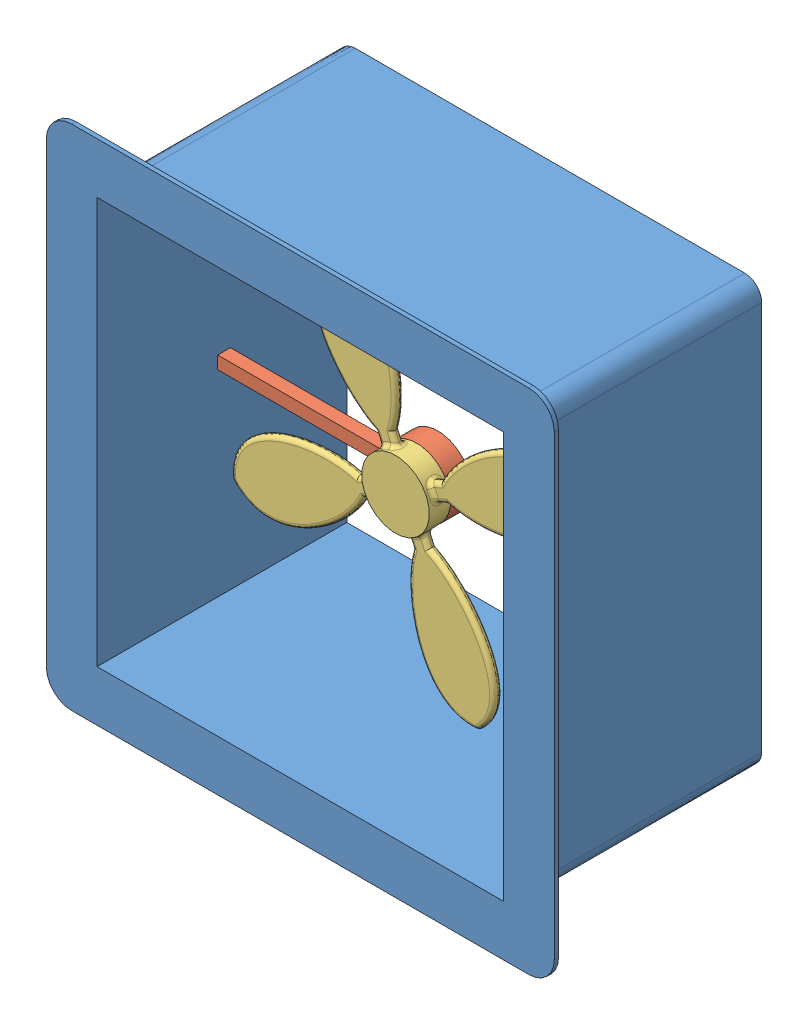
SolidWorks assembly A_Ventilador, configuration Default. Lengths in mm.
Overall size (121.7 121.7 59).
3 component instances, 3 part files, 3 mates.
Components (placement in the parent):
- CasingVentilador-1: CasingVentilador [Default] at (5.1379 70.9552 107.3745) size (120 120 59)
- LigacaoFan_Casing-1: LigacaoFan_Casing [Default] at (5.1379 70.9552 74.8745) size (96 16 5)
- Fan-1: Fan [Default] at (5.1379 70.9552 79.8745) x (-0.915029 -0.403389 0) z (0 0 1) size (92.31 92.31 5)
Mates (geometry in assembly coordinates):
- Coincident2: coincident: line of CasingVentilador-1 through (-42.8621 71.9552 78.3745) axis (0 0 -1); line of LigacaoFan_Casing-1 through (-42.8621 71.9552 78.3745) axis (0 0 -1)
- Coincident3: coincident: line of CasingVentilador-1 through (-42.8621 69.9552 78.3745) axis (0 1 0); line of LigacaoFan_Casing-1 through (-42.8621 69.9552 78.3745) axis (0 1 0)
- Coincident4: coincident: circle of LigacaoFan_Casing-1; circle of Fan-1
